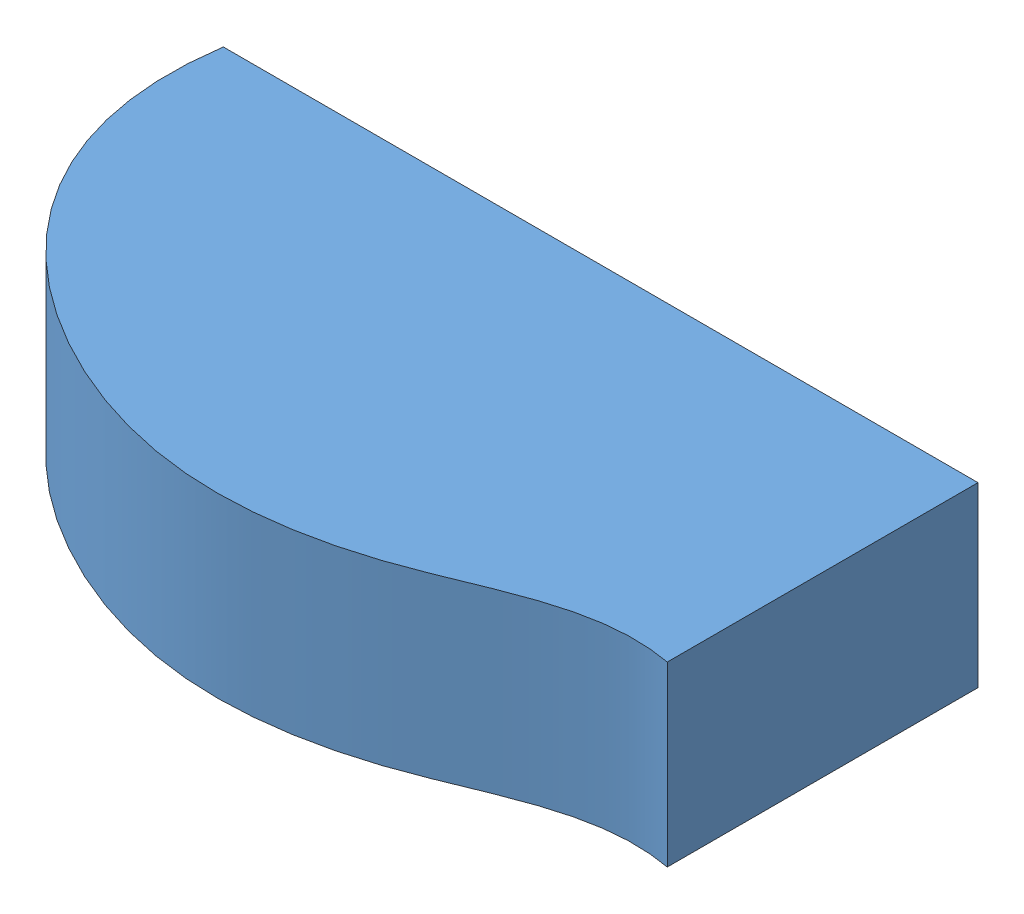
SolidWorks assembly start of fitting parts, configuration Default. Lengths in mm.
Overall size (111.26 25.4 57.7).
2 component instances, 2 part files, 3 mates.
Components (placement in the parent):
- New device-1: New device [Default] at (87.4057 69.8931 60.14) size (111.26 25.4 57.7)
- tilt sensor holder-3: tilt sensor holder [Default] at (16.0557 69.8931 63.315) x (0 -1 0) z (0 0 -1) size (19.05 19.05 26.67)
Mates (geometry in assembly coordinates):
- Coincident8: coincident anti-aligned: plane of New device-1 through (16.0557 48.7531 63.315) normal (-1 0 0); plane of tilt sensor holder-3 through (16.0557 69.8931 63.315) normal (1 0 0)
- Coincident9: coincident anti-aligned: plane of New device-1 through (18.3802 69.8931 113.524) normal (0 -1 0); plane of tilt sensor holder-3 through (8.4357 69.8931 63.315) normal (0 1 0)
- Coincident10: coincident anti-aligned: plane of New device-1 through (-17.7293 47.6681 63.315) normal (0 0 1); plane of tilt sensor holder-3 through (8.4357 69.8931 63.315) normal (0 0 -1)
